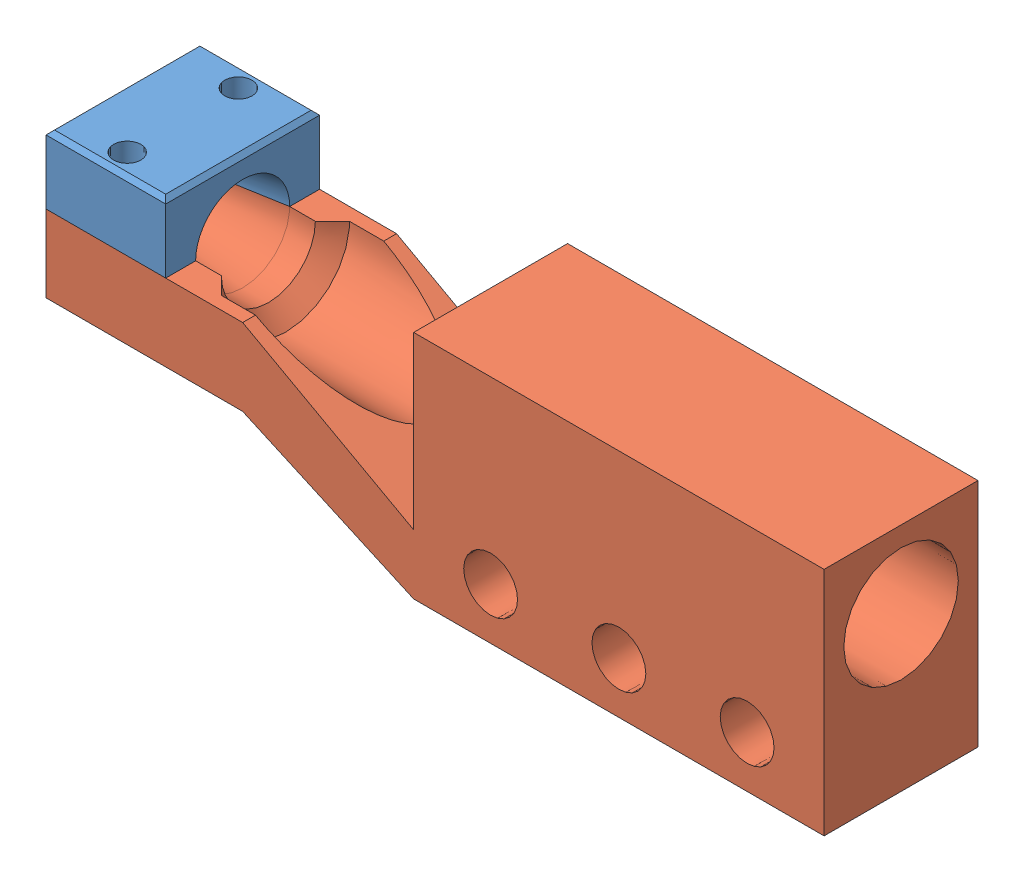
SolidWorks assembly 組合件1, configuration 預設. Lengths in mm.
Overall size (91 27 18).
2 component instances, 2 part files, 6 mates.
Components (placement in the parent):
- cover-1: cover [預設] at (-60 18.5 0) size (14 8 18)
- handpiece-1: handpiece [預設] at origin size (91 27 18)
Mates (geometry in assembly coordinates):
- 重合/共線/共點1: coincident: plane of handpiece-1 through (0 0 0) normal (0 1 0); plane of assembly
- 重合/共線/共點2: coincident: plane of handpiece-1 through (0 0 0) normal (0 0 1); plane of assembly
- 重合/共線/共點3: coincident: plane of handpiece-1 through (0 0 0) normal (1 0 0); plane of assembly
- 重合/共線/共點4: coincident: plane of cover-1 through (-67 9.0789 9) normal (-1 0 0); plane of handpiece-1 through (-67 0 0) normal (-1 0 0)
- 重合/共線/共點5: coincident: plane of cover-1 through (-67 9.0789 9) normal (0 0 1); plane of handpiece-1 through (-24 3.5 9) normal (0 0 1)
- 重合/共線/共點6: coincident: plane of cover-1 through (-60 14.5 0) normal (0 -1 0); plane of handpiece-1 through (-67 14.5 -9) normal (0 1 0)
